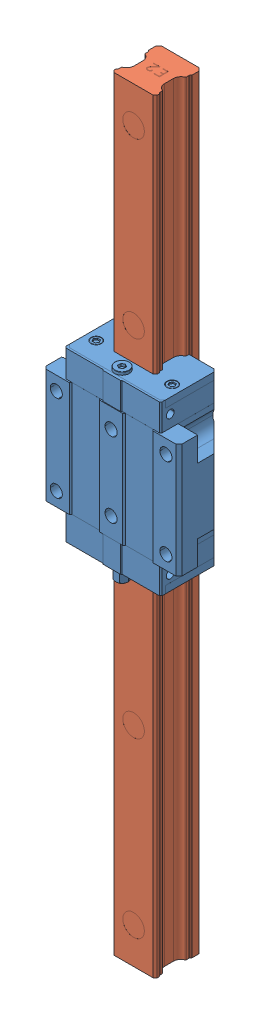
SolidWorks assembly prowadnica, configuration Domyślna. Lengths in mm.
Overall size (47 265 24).
2 component instances, 2 part files, 2 mates.
Components (placement in the parent):
- wozek.stp-1: wozek.stp [Domyślna] at (8.0144 -47.6492 57.9271) size (47 65.53 19.9)
- szyna.stp-2: szyna.stp [Domyślna] at (8.0144 -170.7152 57.9271) size (15 265 16.2)
Mates (geometry in assembly coordinates):
- Wspólnie1: coincident: plane of wozek.stp-1 through (8.0132 25.0118 74.1267) normal (0 0 -1); plane of szyna.stp-2 through (8.0132 94.2848 74.1267) normal (0 0 1)
- Wspólnie2: coincident anti-aligned: plane of wozek.stp-1 through (2.7144 25.0118 67.1521) normal (1 0 0); plane of szyna.stp-2 through (2.7144 94.2848 67.1521) normal (-1 0 0)
